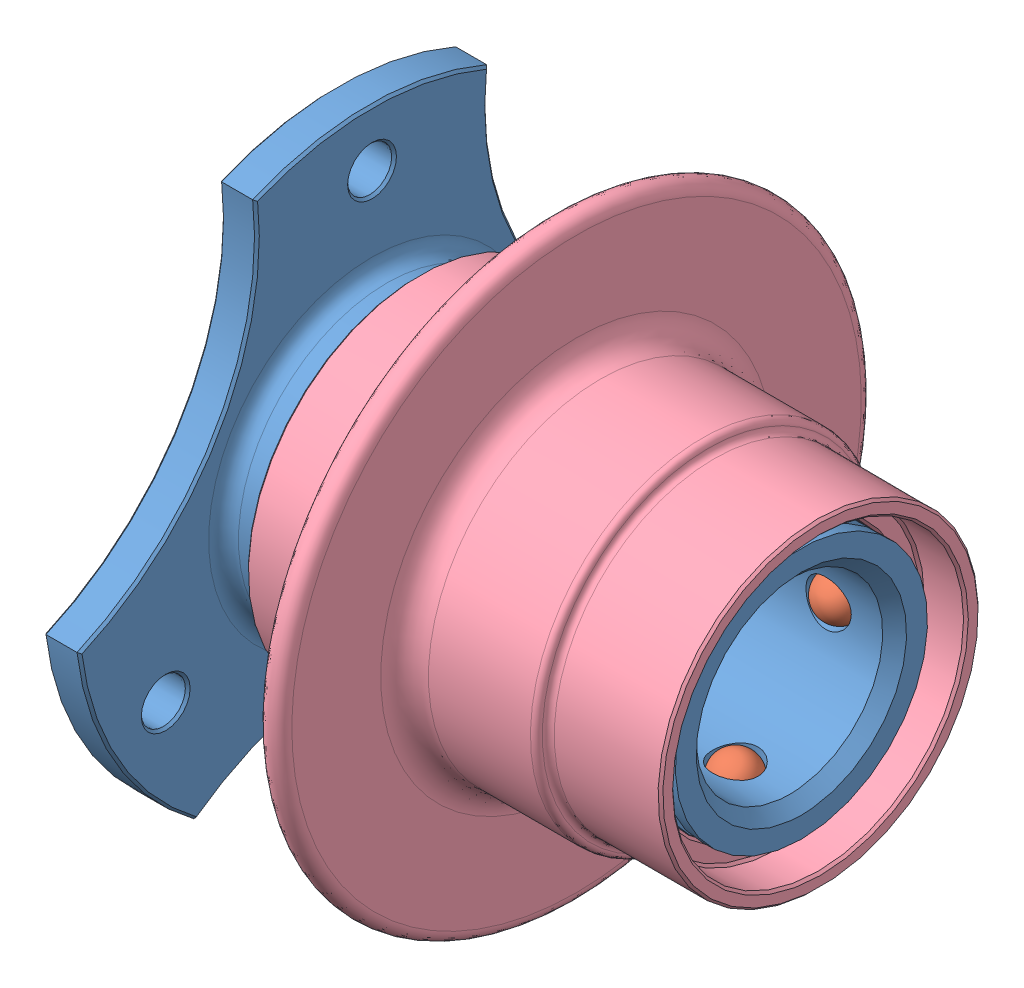
SolidWorks assembly MirrorRaceTechQuickReleasex46x4632, configuration Default. Lengths in mm.
Overall size (51.74 63.18 63.18).
8 component instances, 5 part files, 26 mates.
Components (placement in the parent):
- MirrorReleaseHubx46-1: MirrorReleaseHubx46 [Default] at origin size (49.71 56.55 62.32)
- MirrorReleaseLockBallx46-1: MirrorReleaseLockBallx46 [Default] at (42.4942 0 -11.1316) size (4.72 4.72 4.72)
- MirrorReleaseLockBallx46-2: MirrorReleaseLockBallx46 [Default] at (42.4942 11.1316 0) size (4.72 4.72 4.72)
- MirrorReleaseLockBallx46-3: MirrorReleaseLockBallx46 [Default] at (42.4942 -11.1316 0) size (4.72 4.72 4.72)
- MirrorReleaseLockBallx46-4: MirrorReleaseLockBallx46 [Default] at (42.4942 0 11.1316) size (4.72 4.72 4.72)
- MirrorReleaseSpringx46-1: MirrorReleaseSpringx46 [Default] at (20.6693 0 0) x (0 0 1) z (0 1 0) size (32.55 21.67 32.76)
- MirrorReleaseRingx46-1: MirrorReleaseRingx46 [Default] at (51.562 0 0) x (-1 0 0) z (0 0 -1) size (42.86 63.18 63.18)
- QuickReleaseShaft-1: QuickReleaseShaft [Default] x (-1 0 0) z (0 -0.824535 -0.56581) (suppressed, hidden)
Mates (geometry in assembly coordinates):
- Coincident1: coincident aligned: plane of MirrorReleaseHubx46-1 through (0 0 0) normal (0 0 1); plane of assembly through (0 0 0) normal (0 0 1)
- Coincident2: coincident aligned: plane of MirrorReleaseHubx46-1 through (0 0 0) normal (0 1 0); plane of assembly through (0 0 0) normal (0 1 0)
- Coincident3: coincident aligned: plane of MirrorReleaseHubx46-1 through (0 0 0) normal (1 0 0); plane of assembly through (0 0 0) normal (1 0 0)
- Concentric1: concentric anti-aligned: cylinder of MirrorReleaseHubx46-1 through (0 0 0) axis (-1 0 0) radius 15.8115; cylinder of MirrorReleaseRingx46-1 through (51.562 0 0) axis (1 0 0) radius 13.4938
- Parallel1: parallel aligned: plane of MirrorReleaseRingx46-1 through (51.562 0 0) normal (0 1 0); plane of assembly through (0 0 0) normal (0 1 0)
- Coincident4: coincident aligned: plane of MirrorReleaseSpringx46-1 through (20.6693 0 0) normal (0 1 0); plane of assembly through (0 0 0) normal (0 1 0)
- Coincident5: coincident aligned: plane of MirrorReleaseSpringx46-1 through (20.6693 0 0) normal (0 0 1); plane of assembly through (0 0 0) normal (0 0 1)
- Coincident6: coincident anti-aligned: plane of MirrorReleaseHubx46-1 through (19.812 13.4302 0) normal (1 0 0); plane of MirrorReleaseSpringx46-1 through (19.812 15.8113 15.621) normal (-1 0 0)
- Concentric2: concentric: cylinder of MirrorReleaseHubx46-1 through (42.4942 0 31.1612) axis (0 0 -1) radius 2.413; point of MirrorReleaseLockBallx46-1
- Concentric3: concentric: cylinder of MirrorReleaseHubx46-1 through (42.4942 -25.184 0) axis (0 1 0) radius 2.413; point of MirrorReleaseLockBallx46-2
- Concentric4: concentric: cylinder of MirrorReleaseHubx46-1 through (42.4942 -25.184 0) axis (0 1 0) radius 2.413; point of MirrorReleaseLockBallx46-3
- Concentric5: concentric: cylinder of MirrorReleaseHubx46-1 through (42.4942 0 31.1612) axis (0 0 -1) radius 2.413; point of MirrorReleaseLockBallx46-4
- Parallel2: parallel aligned: plane of MirrorReleaseLockBallx46-1 through (42.4942 0 -11.1316) normal (0 1 0); plane of assembly through (0 0 0) normal (0 1 0)
- Parallel3: parallel aligned: plane of MirrorReleaseLockBallx46-1 through (42.4942 0 -11.1316) normal (0 0 1); plane of assembly through (0 0 0) normal (0 0 1)
- Parallel4: parallel aligned: plane of MirrorReleaseLockBallx46-2 through (42.4942 11.1316 0) normal (0 0 1); plane of assembly through (0 0 0) normal (0 0 1)
- Parallel5: parallel aligned: plane of MirrorReleaseLockBallx46-2 through (42.4942 11.1316 0) normal (0 1 0); plane of assembly through (0 0 0) normal (0 1 0)
- Parallel6: parallel aligned: plane of MirrorReleaseLockBallx46-3 through (42.4942 -11.1316 0) normal (0 1 0); plane of assembly through (0 0 0) normal (0 1 0)
- Parallel7: parallel aligned: plane of MirrorReleaseLockBallx46-3 through (42.4942 -11.1316 0) normal (0 0 1); plane of assembly through (0 0 0) normal (0 0 1)
- Parallel8: parallel aligned: plane of MirrorReleaseLockBallx46-4 through (42.4942 0 11.1316) normal (0 0 1); plane of assembly through (0 0 0) normal (0 0 1)
- Parallel9: parallel aligned: plane of MirrorReleaseLockBallx46-4 through (42.4942 0 11.1316) normal (0 1 0); plane of assembly through (0 0 0) normal (0 1 0)
- Tangent1: tangent aligned: sphere of MirrorReleaseLockBallx46-1; cylinder of MirrorReleaseRingx46-1 through (51.562 0 0) axis (1 0 0) radius 13.4938
- Tangent2: tangent aligned: sphere of MirrorReleaseLockBallx46-2; cylinder of MirrorReleaseRingx46-1 through (51.562 0 0) axis (1 0 0) radius 13.4938
- Tangent3: tangent aligned: sphere of MirrorReleaseLockBallx46-4; cylinder of MirrorReleaseRingx46-1 through (51.562 0 0) axis (1 0 0) radius 13.4938
- Tangent4: tangent aligned: sphere of MirrorReleaseLockBallx46-3; cylinder of MirrorReleaseRingx46-1 through (51.562 0 0) axis (1 0 0) radius 13.4938
- Coincident7: coincident aligned: plane of MirrorReleaseHubx46-1 through (0 31.369 0) normal (-1 0 0); plane of QuickReleaseShaft-1 through (0 4.6708 -6.8065) normal (-1 0 0)
- Concentric6: concentric aligned: cylinder of MirrorReleaseHubx46-1 through (0 0 0) axis (-1 0 0) radius 9.9378; cylinder of QuickReleaseShaft-1 through (0 0 0) axis (-1 0 0) radius 5.5245
